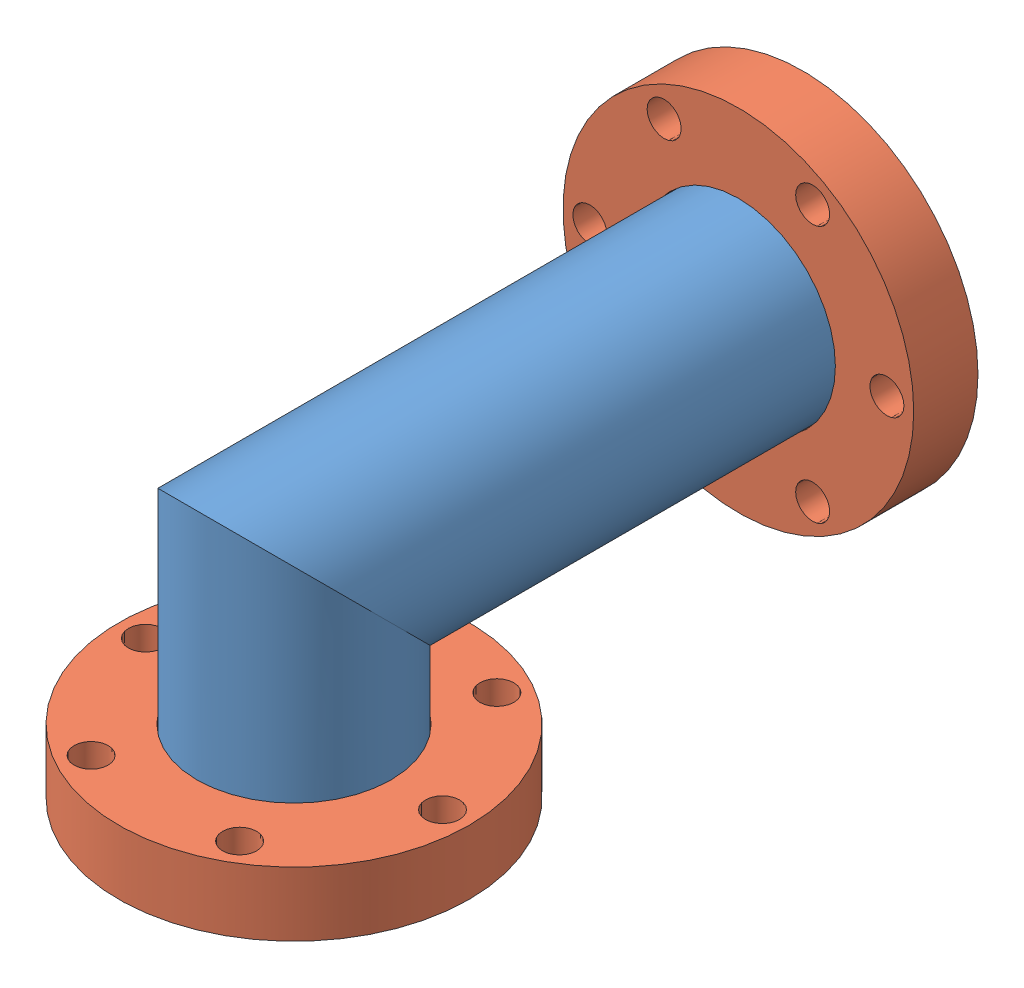
SolidWorks assembly custom_elbow_2in75, configuration Default. Lengths in mm.
Overall size (69.34 74.27 135.23).
3 component instances, 2 part files, 7 mates.
Components (placement in the parent):
- elbow^custom_elbow_2in75-1: elbow^custom_elbow_2in75 [Default] at origin size (38.1 53.34 114.3) (virtual)
- 110014 (2.75 X 1.5 NR)-1: 110014 (2.75 X 1.5 NR) [Default] at (0 0 1.0414) x (0 0 -1) z (1 0 0) size (12.7 69.34 69.34)
- 110014 (2.75 X 1.5 NR)-2: 110014 (2.75 X 1.5 NR) [Default] at (0 -33.2486 95.25) x (0 -1 0) z (1 0 0) size (12.7 69.34 69.34)
Mates (geometry in assembly coordinates):
- Coincident1: coincident aligned: plane of elbow^custom_elbow_2in75-1 through (0 0 0) normal (0 0 1); plane of assembly through (0 0 0) normal (0 0 1)
- Coincident2: coincident aligned: plane of elbow^custom_elbow_2in75-1 through (0 0 0) normal (0 1 0); plane of assembly through (0 0 0) normal (0 1 0)
- Coincident3: coincident aligned: plane of elbow^custom_elbow_2in75-1 through (0 0 0) normal (1 0 0); plane of assembly through (0 0 0) normal (1 0 0)
- Coincident11: coincident anti-aligned: plane of elbow^custom_elbow_2in75-1 through (0 0 0) normal (0 0 -1); plane of 110014 (2.75 X 1.5 NR)-1 through (0 -18.3197 0) normal (0 0 1)
- Concentric3: concentric anti-aligned: cylinder of elbow^custom_elbow_2in75-1 through (0 0 149.1315) axis (0 0 -1) radius 19.05; cylinder of 110014 (2.75 X 1.5 NR)-1 through (0 0 3.6957) axis (0 0 1) radius 19.177
- Concentric4: concentric anti-aligned: cylinder of elbow^custom_elbow_2in75-1 through (0 0 95.25) axis (0 -1 0) radius 19.05; cylinder of 110014 (2.75 X 1.5 NR)-2 through (0 -30.5943 95.25) axis (0 1 0) radius 19.177
- Coincident12: coincident anti-aligned: plane of elbow^custom_elbow_2in75-1 through (0 -34.29 95.25) normal (0 -1 0); plane of 110014 (2.75 X 1.5 NR)-2 through (0 -34.29 113.5697) normal (0 1 0)
